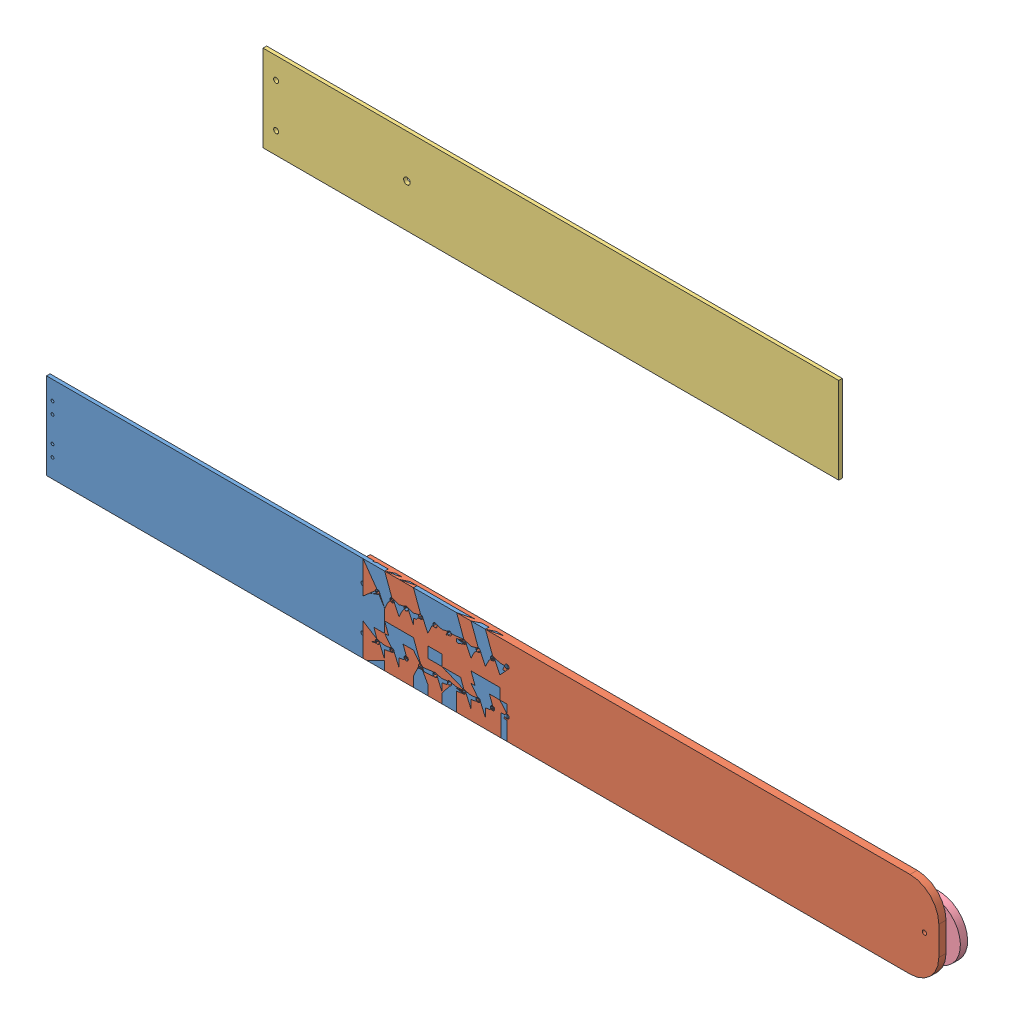
SolidWorks assembly Assem1, configuration Default. Lengths in mm.
Overall size (800.1 297.91 127.45).
4 component instances, 4 part files, 3 mates.
Components (placement in the parent):
- v5_vertical-1: v5_vertical [Default] at (-317.664 -19.9287 195.0759) size (406.4 76.2 3.17)
- v5_vertical_2-2: v5_vertical_2 [Default] at (-38.264 -19.9287 191.9009) size (508 76.2 6.35)
- v5_plank-1: v5_plank [Default] at (-250.8467 201.7775 70.8026) size (508 76.2 3.17)
- v5_wheel-1: v5_wheel [Default] at (457.036 18.1713 191.9009) x (1 0 0) z (0 1 0) size (50.8 6.35 50.8)
Mates (geometry in assembly coordinates):
- Coincident1: coincident aligned: circle of v5_vertical-1; circle of v5_vertical_2-2
- Coincident3: coincident: plane of v5_vertical_2-2 through (-38.264 56.2713 191.9009) normal (0 0 -1); plane of v5_wheel-1 through (457.036 18.1713 191.9009) normal (0 0 1)
- Concentric2: concentric anti-aligned: circle of v5_vertical_2-2; circle of v5_wheel-1
